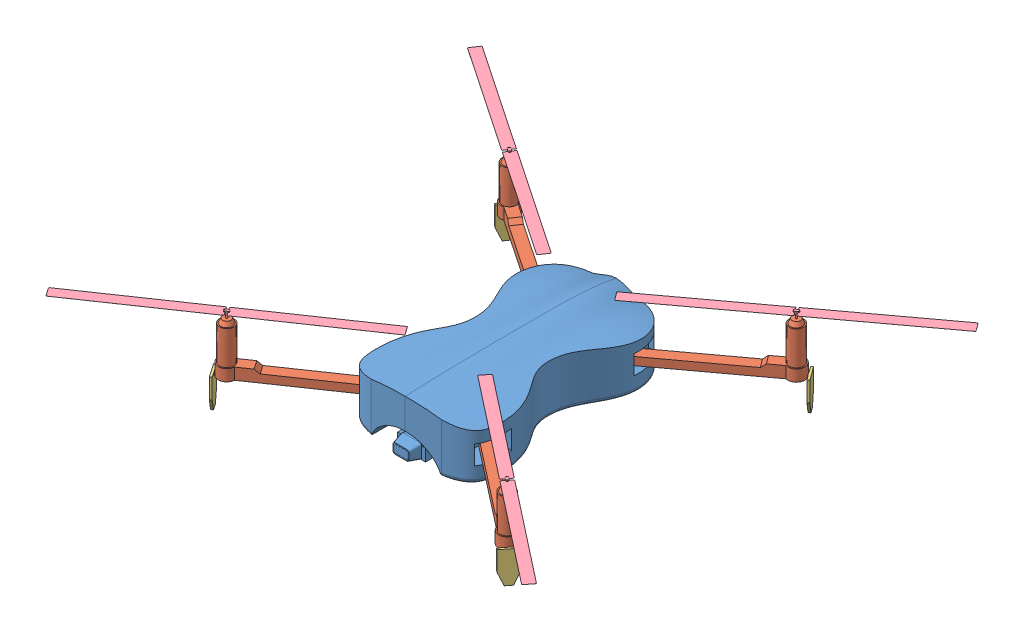
SolidWorks assembly Assem1, configuration Default. Lengths in mm.
Overall size (237.34 40.3 215.21).
13 component instances, 4 part files, 27 mates.
Components (placement in the parent):
- Корпус-1: Корпус [Default] at (39.6457 47.3344 88.8379) size (67.65 28.45 107.59)
- Блок-1: Блок [Default] at (95.0853 51.3484 151.2749) x (0.788377 0 0.615192) z (-0.615192 0 0.788377) size (59.86 25.43 8)
- Блок-2: Блок [Default] at (-16.2814 51.3484 29.3084) x (-0.829417 0 -0.55863) z (0.55863 0 -0.829417) size (59.86 25.43 8)
- Блок-3: Блок [Default] at (-18.759 51.3484 147.2245) x (-0.824652 0 0.56564) z (-0.56564 0 -0.824652) size (59.86 25.43 8)
- Блок-4: Блок [Default] at (96.1046 51.3484 30.0623) x (0.804591 0 -0.593829) z (0.593829 0 0.804591) size (59.86 25.43 8)
- Ніжка-1: Ніжка [Default] at (110.3949 49.6851 161.5645) x (-0.615192 0 0.788377) z (-0.788377 0 -0.615192) size (8 15 2.4)
- Ніжка-2: Ніжка [Default] at (110.1333 49.6851 18.0849) x (0.593829 0 0.804591) z (-0.804591 0 0.593829) size (8 15 2.4)
- Ніжка-3: Ніжка [Default] at (-32.2723 49.6851 20.1131) x (0.55863 0 -0.829417) z (0.829417 0 0.55863) size (8 15 2.4)
- Ніжка-4: Ніжка [Default] at (-33.1937 49.6851 158.7094) x (-0.56564 0 -0.824652) z (0.824652 0 -0.56564) size (8 15 2.4)
- гвнит-1: гвнит [Default] at (105.9607 78.3484 21.1645) x (0.803844 0 -0.59484) z (0.59484 0 0.803844) size (122.2 3.2 5)
- гвнит-2: гвнит [Default] at (106.3065 78.3484 158.3742) x (-0.787215 0 -0.616679) z (0.616679 0 -0.787215) size (122.2 3.2 5)
- гвнит-3: гвнит [Default] at (-27.971 78.3484 23.0101) x (0.82838 0 0.560166) z (-0.560166 0 0.82838) size (122.2 3.2 5)
- гвнит-4: гвнит [Default] at (-28.9171 78.3484 155.776) x (0.825696 0 -0.564116) z (0.564116 0 0.825696) size (122.2 3.2 5)
Mates (geometry in assembly coordinates):
- Concentric1: concentric aligned: cylinder of Корпус-1 through (64.9686 57.9162 126.1172) axis (0 -1 0) radius 1; cylinder of Блок-1 through (64.9686 57.9162 126.1172) axis (0 -1 0) radius 1
- Coincident1: coincident anti-aligned: plane of Корпус-1 through (59.6457 54.9162 134.2928) normal (0 1 0); plane of Блок-1 through (64.6312 54.9162 120.8602) normal (0 -1 0)
- Concentric2: concentric aligned: cylinder of Корпус-1 through (63.7727 57.9162 52.3014) axis (0 -1 0) radius 1; cylinder of Блок-4 through (63.7727 57.9162 52.3014) axis (0 -1 0) radius 1
- Coincident2: coincident anti-aligned: plane of Корпус-1 through (59.6457 54.9162 59.7617) normal (0 1 0); plane of Блок-4 through (58.6395 54.9162 51.1185) normal (0 -1 0)
- Concentric3: concentric aligned: cylinder of Корпус-1 through (14.3228 57.9162 126.1172) axis (0 -1 0) radius 1; cylinder of Блок-3 through (14.3228 57.9162 126.1172) axis (0 -1 0) radius 1
- Coincident4: coincident anti-aligned: plane of Корпус-1 through (19.6457 54.9162 134.2928) normal (0 1 0); plane of Блок-3 through (19.412 54.9162 127.4769) normal (0 -1 0)
- Concentric4: concentric aligned: cylinder of Корпус-1 through (15.5187 57.9162 52.3014) axis (0 -1 0) radius 1; cylinder of Блок-2 through (15.5187 57.9162 52.3014) axis (0 -1 0) radius 1
- Coincident5: coincident anti-aligned: plane of Корпус-1 through (19.6457 54.9162 59.7617) normal (0 1 0); plane of Блок-2 through (16.1272 54.9162 57.5339) normal (0 -1 0)
- Coincident8: coincident anti-aligned: plane of Блок-1 through (108.3296 51.3484 160.3339) normal (0.79945 0 0.600733); plane of Ніжка-1 through (109.1143 49.6851 159.2896) normal (-0.79945 0 -0.600733)
- Coincident9: coincident anti-aligned: plane of Ніжка-1 through (109.715 55.9162 158.4902) normal (0 1 0); plane of Блок-1 through (108.5135 55.9162 160.0891) normal (0 -1 0)
- Coincident10: coincident anti-aligned: plane of Блок-1 through (108.5135 54.9162 160.0891) normal (0.600733 0 -0.79945); plane of Ніжка-1 through (108.5135 55.9162 160.0891) normal (-0.600733 0 0.79945)
- Coincident11: coincident anti-aligned: plane of Ніжка-2 through (108.2022 49.6851 19.5101) normal (-0.804591 0 0.593829); plane of Блок-4 through (108.9779 51.3484 20.5611) normal (0.804591 0 -0.593829)
- Coincident12: coincident anti-aligned: plane of Ніжка-2 through (107.6084 55.9162 18.7055) normal (0 1 0); plane of Блок-4 through (108.7961 55.9162 20.3147) normal (0 -1 0)
- Coincident13: coincident anti-aligned: plane of Ніжка-2 through (107.6084 55.9162 18.7055) normal (-0.593829 0 -0.804591); plane of Блок-4 through (107.6084 54.9162 18.7055) normal (0.593829 0 0.804591)
- Coincident14: coincident anti-aligned: plane of Ніжка-3 through (-30.2817 49.6851 21.4538) normal (0.829417 0 0.55863); plane of Блок-2 through (-29.552 51.3484 20.3704) normal (-0.829417 0 -0.55863)
- Coincident15: coincident anti-aligned: plane of Блок-2 through (-29.7231 55.9162 20.6244) normal (0 -1 0); plane of Ніжка-3 through (-30.8404 55.9162 22.2832) normal (0 1 0)
- Coincident16: coincident anti-aligned: plane of Блок-2 through (-29.7231 54.9162 20.6244) normal (-0.55863 0 0.829417); plane of Ніжка-3 through (-29.7231 55.9162 20.6244) normal (0.55863 0 -0.829417)
- Coincident17: coincident anti-aligned: plane of Ніжка-4 through (-31.2145 49.6851 157.3518) normal (0.824652 0 -0.56564); plane of Блок-3 through (-31.9534 51.3484 156.2747) normal (-0.824652 0 0.56564)
- Coincident19: coincident anti-aligned: plane of Ніжка-4 through (-31.7802 55.9162 156.5272) normal (-0.56564 0 -0.824652); plane of Блок-3 through (-31.7802 54.9162 156.5272) normal (0.56564 0 0.824652)
- Concentric5: concentric aligned: cylinder of Блок-4 through (105.9607 80.3484 21.1645) axis (0 -1 0) radius 0.3; cylinder of гвнит-1 through (105.9607 80.3484 21.1645) axis (0 -1 0) radius 0.3
- Coincident21: coincident anti-aligned: plane of Блок-4 through (105.9607 78.3484 21.1645) normal (0 1 0); plane of гвнит-1 through (105.9607 78.3484 21.1645) normal (0 -1 0)
- Concentric6: concentric aligned: cylinder of Блок-2 through (-27.971 80.3484 23.0101) axis (0 -1 0) radius 0.3; cylinder of гвнит-3 through (-27.971 80.3484 23.0101) axis (0 -1 0) radius 0.3
- Concentric7: concentric aligned: cylinder of Блок-3 through (-28.9171 80.3484 155.776) axis (0 -1 0) radius 0.3; cylinder of гвнит-4 through (-28.9171 80.3484 155.776) axis (0 -1 0) radius 0.3
- Coincident24: coincident anti-aligned: plane of Блок-3 through (-28.9171 78.3484 155.776) normal (0 1 0); plane of гвнит-4 through (-28.9171 78.3484 155.776) normal (0 -1 0)
- Concentric8: concentric aligned: cylinder of Блок-1 through (106.887 80.3484 157.616) axis (0 -1 0) radius 0.3; cylinder of гвнит-2 through (106.887 80.3484 157.616) axis (0 -1 0) radius 0.3
- Coincident25: coincident anti-aligned: plane of Блок-1 through (106.887 78.3484 157.616) normal (0 1 0); plane of гвнит-2 through (106.887 78.3484 157.616) normal (0 -1 0)
- Coincident26: coincident anti-aligned: plane of Блок-2 through (-27.971 78.3484 23.0101) normal (0 1 0); plane of гвнит-3 through (-27.971 78.3484 23.0101) normal (0 -1 0)
